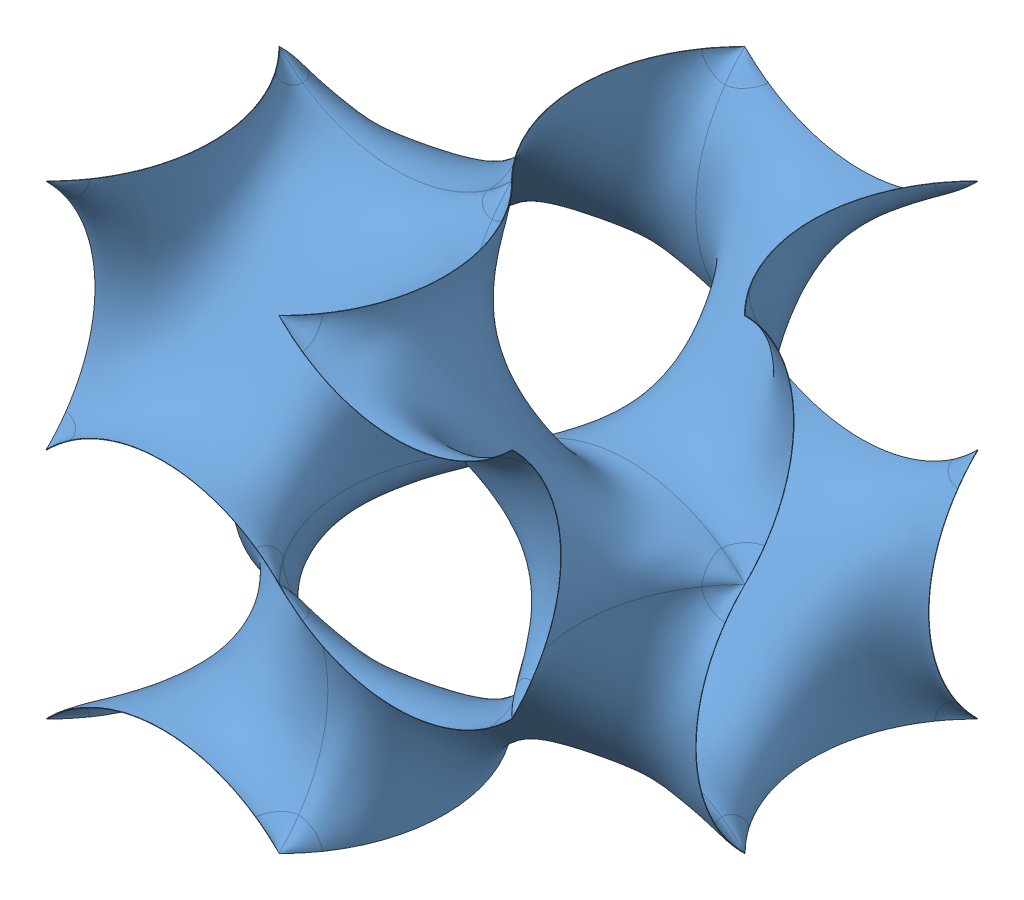
SolidWorks assembly Gyroid2Assy, configuration Default. Lengths in mm.
Overall size (20.09 20.07 20.11).
9 component instances, 2 part files, 38 mates.
Components (placement in the parent):
- Gyroid2-25: Gyroid2 [Default] at origin size (10.05 10.05 10.05) (hidden)
- Gyroid2-26: Gyroid2 [Default] at (0 0 -10) x (-1 0 0) z (0 0 -1) size (10.05 10.05 10.05) (hidden)
- Gyroid2-27: Gyroid2 [Default] at (10 0 -10) x (1 0 0) z (0 0 -1) size (10.05 10.05 10.05) (hidden)
- Gyroid2-28: Gyroid2 [Default] at (10 0 0) x (0 0 1) z (0 -1 0) size (10.05 10.05 10.05) (hidden)
- Gyroid2-32: Gyroid2 [Default] at (10 -10 0) x (-1 0 0) z (0 0 -1) size (10.05 10.05 10.05) (hidden)
- Gyroid2-33: Gyroid2 [Default] at (0 -10 0) x (0 -1 0) z (1 0 0) size (10.05 10.05 10.05) (hidden)
- Gyroid2-34: Gyroid2 [Default] at (10 -10 -10) size (10.05 10.05 10.05) (hidden)
- Gyroid2-36: Gyroid2 [Default] at (0 -10 -10) x (-1 0 0) z (0 0 1) size (10.05 10.05 10.05) (hidden)
- Part1^Gyroid2Assy-1: Part1^Gyroid2Assy [Default] at origin size (20.09 20.07 20.11) (virtual)
Mates (geometry in assembly coordinates):
- Coincident1: coincident aligned: plane of Gyroid-25 through (0 0 0) normal (0 0 1)
- Coincident2: coincident aligned: plane of Gyroid-25 through (0 0 0) normal (0 1 0)
- Coincident3: coincident aligned: plane of Gyroid-25 through (0 0 0) normal (1 0 0)
- Coincident4: coincident aligned: plane of Gyroid-26 through (0 0 -10) normal (0 1 0)
- Distance2: distance = 10 mm anti-aligned: plane of Gyroid-26 through (0 0 -10) normal (0 0 -1)
- Coincident5: coincident aligned: plane of Gyroid-26 through (0 0 -10) normal (0 1 0)
- Coincident6: coincident anti-aligned: plane of Gyroid-26 through (0 0 -10) normal (-1 0 0)
- Coincident7: coincident anti-aligned: plane of Gyroid r7-4 through (10 0 0.6251) normal (0 -1 0)
- Distance4: distance = 10 mm aligned: plane of Gyroid r7-4 through (10 0 0) normal (1 0 0)
- Coincident8: coincident anti-aligned: plane of Gyroid r7-4 through (10 0 0.6251) normal (0 0 -1)
- Coincident9: coincident anti-aligned: plane of Gyroid r7-7 through (10 0 0) normal (0 -1 0)
- Distance5: distance = 10 mm aligned: plane of Gyroid r7-7 through (10 0 0) normal (1 0 0)
- Coincident10: coincident anti-aligned: plane of Gyroid r7-7 through (10 0 0) normal (0 0 -1)
- Distance6: distance = 10 mm anti-aligned: plane of Gyroid r7-8 through (10 0 -10) normal (-1 0 0)
- Distance8: distance = 10 mm: plane of assembly through (0 0 0) normal (0 0 1); plane of assembly; plane of Gyroid r7-8 through (10 0 -10) normal (0 0 1)
- Coincident12: coincident anti-aligned: plane of Gyroid r7-8 through (10 0 -10) normal (0 -1 0)
- Coincident13: coincident anti-aligned: plane of Gyroid-27 through (10 0 -10) normal (0 -1 0)
- Distance9: distance = 10 mm aligned: plane of Gyroid-27 through (10 0 -10) normal (1 0 0)
- Distance10: distance = 10 mm anti-aligned: plane of Gyroid-27 through (10 0 -10) normal (0 0 -1)
- Coincident14: coincident anti-aligned: plane of Gyroid-28 through (10 0 0) normal (0 -1 0)
- Coincident15: coincident aligned: plane of Gyroid-28 through (10 0 0) normal (0 0 1)
- Distance11: distance = 10 mm anti-aligned: plane of Gyroid-28 through (10 0 0) normal (-1 0 0)
- Distance12: distance = 10 mm aligned: plane of Gyroid-32 through (10 -10 0) normal (0 1 0)
- Coincident17: coincident anti-aligned: plane of Gyroid-32 through (10 -10 0) normal (0 0 -1)
- Distance13: distance = 10 mm anti-aligned: plane of Gyroid-32 through (10 -10 0) normal (-1 0 0)
- Coincident18: coincident aligned: plane of Gyroid-33 through (0 -10 0) normal (1 0 0)
- Coincident19: coincident anti-aligned: plane of Gyroid-33 through (0 -10 0) normal (0 0 -1)
- Distance14: distance = 10 mm anti-aligned: plane of Gyroid-33 through (0 -10 0) normal (0 -1 0)
- Distance15: distance = 10 mm aligned: plane of Gyroid-34 through (10 -10 -10) normal (0 0 1)
- Distance16: distance = 10 mm aligned: plane of Gyroid-34 through (10 -10 -10) normal (0 1 0)
- Distance17: distance = 10 mm: plane of assembly through (0 0 0) normal (1 0 0); plane of Gyroid-34 through (10 -10 -10) normal (1 0 0)
- Distance18: distance = 10 mm aligned: plane of Gyroid-36 through (0 -10 -10) normal (0 0 1)
- Distance19: distance = 10 mm: plane of assembly through (0 0 0) normal (0 1 0); plane of Gyroid-36 through (0 -10 -10) normal (0 -1 0)
- Coincident21: coincident anti-aligned: plane of Gyroid-36 through (0 -10 -10) normal (-1 0 0)
- InPlace1: in place: plane of ? through (0 0 0) normal (0 0 1); moOrthogonalPlaneRef_w of ? through (0 0 0) normal (0 1 0); plane of ? through (0 0 0) normal (1 0 0); unknown of ?
- Coincident22: coincident aligned: 
- Coincident23: coincident aligned: plane of Gyroid 8x Part-1 through (0 0 0) normal (0 1 0)
- Coincident24: coincident anti-aligned: plane of Gyroid 8x Part-1 through (0 0 0) normal (1 0 0)
